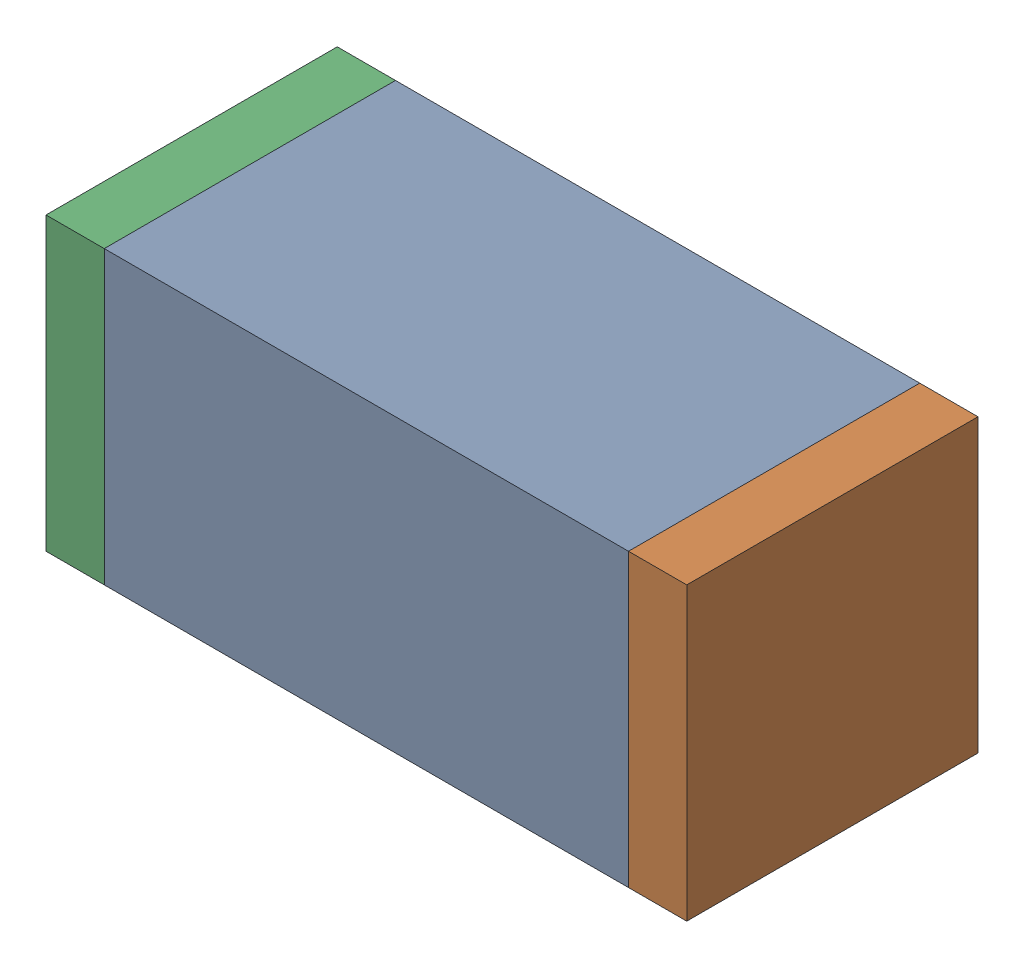
SolidWorks assembly C66, configuration Default. Lengths in mm.
Overall size (1.1 0.5 0.5).
6 component instances, 2 part files, 0 mates.
Components (placement in the parent):
- 836749680-1: 836749680 [Default] at (108.4 54.75 0) size (0.9 0.5 0.5)
  - Extruded_4-1: Extruded_4 [Default] at origin size (0.9 0.5 0.5)
- 810156080-1: 810156080 [Default] at (108.9 54.75 0) size (0.1 0.5 0.5)
  - Extruded_5-1: Extruded_5 [Default] at origin size (0.1 0.5 0.5)
- 810156080-2: 810156080 [Default] at (107.9 54.75 0) size (0.1 0.5 0.5)
  - Extruded_5-1: Extruded_5 [Default] at origin size (0.1 0.5 0.5)
